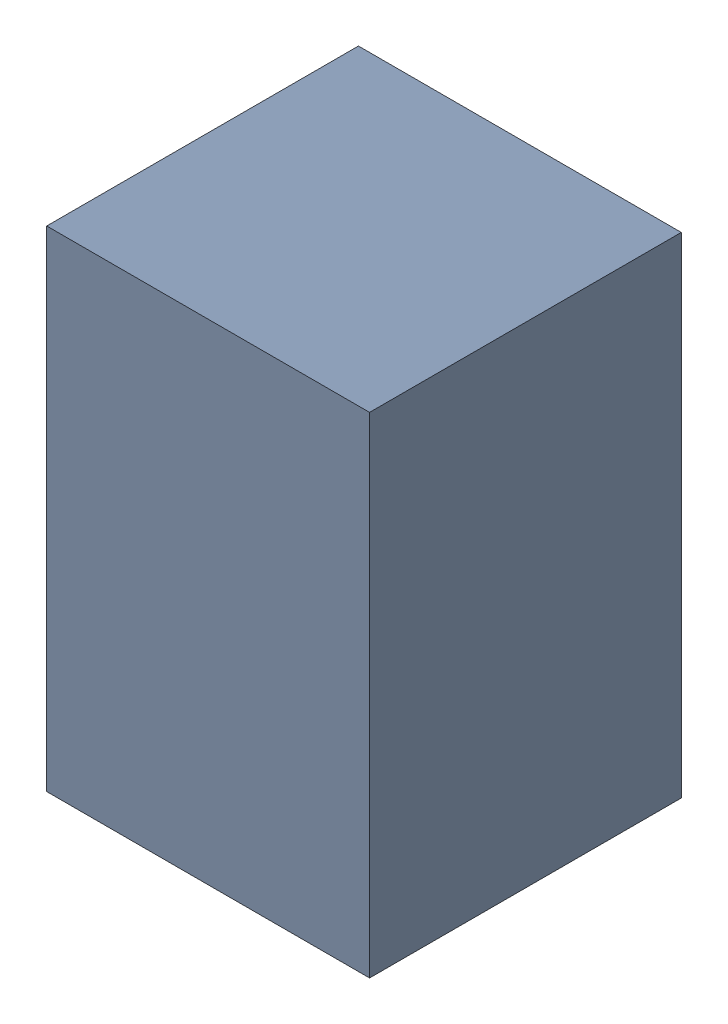
SolidWorks assembly D3-2, configuration Default. Lengths in mm.
Overall size (1.45 2.2 1.4).
2 component instances, 1 part files, 0 mates.
Components (placement in the parent):
- 959209888-2-1: 959209888-2 [Default] at (108.585 90.769 0) size (1.45 2.2 1.4)
  - Extruded-91-1: Extruded-91 [Default] at origin size (1.45 2.2 1.4)
